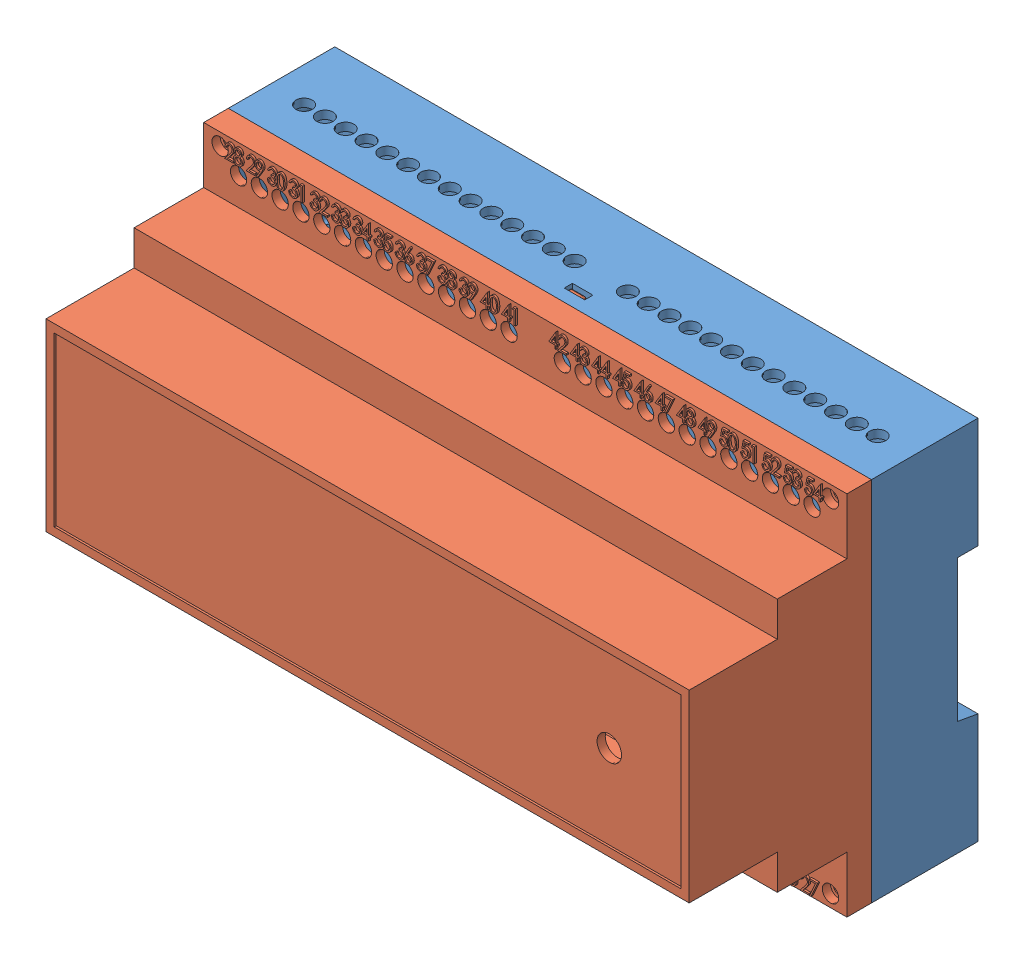
SolidWorks assembly Assem1, configuration Default. Lengths in mm.
Overall size (157 89.5 70.5).
4 component instances, 4 part files, 8 mates.
Components (placement in the parent):
- lower-1: lower [Default] at (-37.3916 9.4457 -0.4362) size (157 89.5 27.5)
- upper-1: upper [Default] at (-37.3916 9.4457 25.5638) x (-1 0 0) z (0 0 1) size (157 89.5 49)
- MiddleDinPlate-1: MiddleDinPlate [Default] at (-37.3916 9.6457 31.5638) size (152 57 2)
- sampleboard-1: sampleboard [Default] at (-49.3916 9.6957 49.5638) size (98 40.59 15.1)
Mates (geometry in assembly coordinates):
- Coincident1: coincident anti-aligned: plane of lower-1 through (-37.3916 9.4457 25.5638) normal (0 0 1); plane of upper-1 through (-37.3916 9.4457 25.5638) normal (0 0 -1)
- Coincident4: coincident aligned: plane of lower-1 through (41.1084 54.1957 25.5638) normal (1 0 0); plane of upper-1 through (41.1084 -35.3043 70.0638) normal (1 0 0)
- Coincident5: coincident aligned: plane of lower-1 through (-115.8916 54.1957 25.5638) normal (0 1 0); plane of upper-1 through (41.1084 54.1957 70.0638) normal (0 1 0)
- Concentric1: concentric anti-aligned: circle of upper-1; circle of MiddleDinPlate-1
- Distance1: distance = 13 mm anti-aligned: plane of MiddleDinPlate-1 through (-37.3916 9.6457 33.5638) normal (0 0 1); plane of upper-1 through (-37.3916 9.4457 46.5638) normal (0 0 -1)
- Distance2: distance = 16 mm anti-aligned: plane of sampleboard-1 through (-49.3916 9.6957 49.5638) normal (0 0 -1); plane of MiddleDinPlate-1 through (-37.3916 9.6457 33.5638) normal (0 0 1)
- Concentric2: concentric aligned: cylinder of MiddleDinPlate-1 through (-5.3916 -5.3043 31.5638) axis (0 0 1) radius 1.5; cylinder of sampleboard-1 through (-5.3916 -5.3043 49.5638) axis (0 0 1) radius 1.6
- Concentric3: concentric anti-aligned: circle of MiddleDinPlate-1; circle of sampleboard-1
